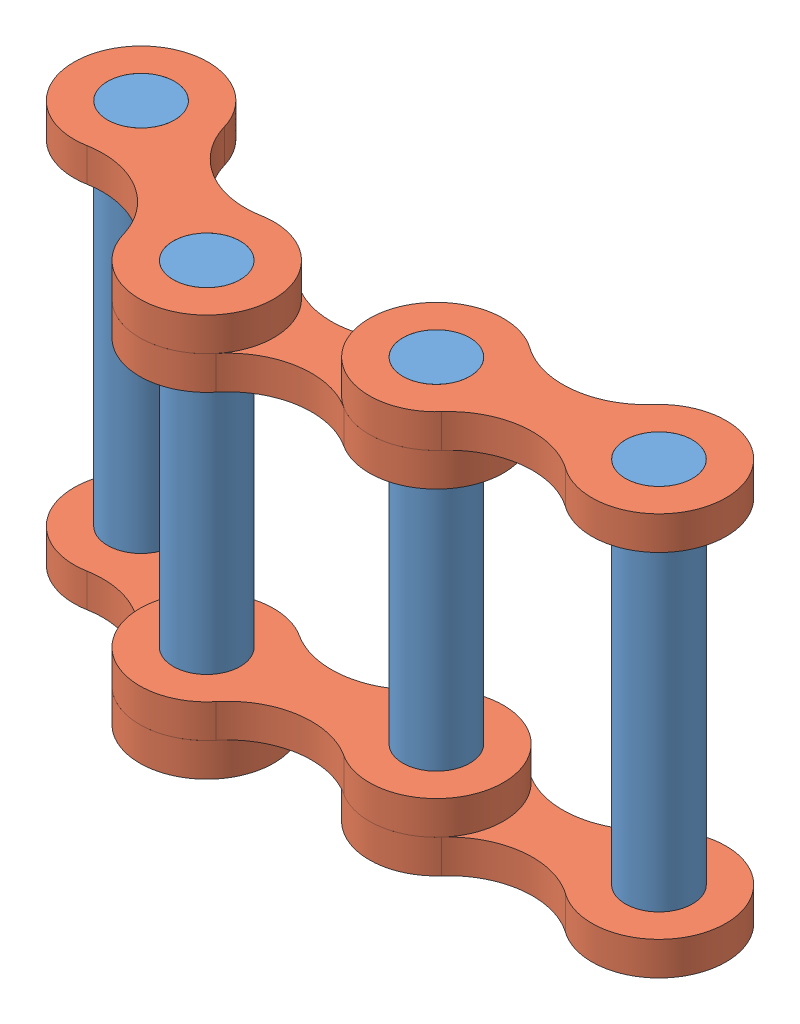
SolidWorks assembly 3linkgearchain, configuration Default. Lengths in mm.
Overall size (10.98 6 4.33).
10 component instances, 2 part files, 23 mates.
Components (placement in the parent):
- bar-1: bar [Default] at (1.6801 0.1043 2.3962) size (1 6 1)
- bar-2: bar [Default] at (-1.2839 0.1043 2.86) x (0.903428 0 0.428741) z (-0.428741 0 0.903428) size (1 6 1)
- bar-3: bar [Default] at (4.6606 0.1043 2.0548) x (-0.977812 0 -0.209483) z (0.209483 0 -0.977812) size (1 6 1)
- link-1: link [Default] at (1.6801 5.6043 2.3962) x (0.993502 0 -0.113816) z (0.113816 0 0.993502) size (5 0.5 2)
- link-2: link [Default] at (-1.2839 5.1043 2.86) x (0.987976 0 -0.154604) z (0.154604 0 0.987976) size (5 0.5 2)
- link-3: link [Default] at (-1.2839 0.6043 2.86) x (0.987976 0 -0.154604) z (0.154604 0 0.987976) size (5 0.5 2)
- link-4: link [Default] at (1.6801 0.1043 2.3962) x (0.993502 0 -0.113816) z (0.113816 0 0.993502) size (5 0.5 2)
- link-6: link [Default] at (-3.8378 5.6043 1.286) x (0.851305 0 0.524672) z (-0.524672 0 0.851305) size (5 0.5 2)
- link-7: link [Default] at (-3.8378 0.1043 1.286) x (0.851305 0 0.524672) z (-0.524672 0 0.851305) size (5 0.5 2)
- bar-5: bar [Default] at (-3.8378 0.1043 1.286) size (1 6 1)
Mates (geometry in assembly coordinates):
- Concentric1: concentric aligned: cylinder of bar-3 through (4.6606 6.1043 2.0548) axis (0 -1 0) radius 0.5; cylinder of link-1 through (4.6606 6.1043 2.0548) axis (0 -1 0) radius 0.5
- Concentric2: concentric aligned: cylinder of bar-1 through (1.6801 6.1043 2.3962) axis (0 -1 0) radius 0.5; cylinder of link-1 through (1.6801 6.1043 2.3962) axis (0 -1 0) radius 0.5
- Concentric3: concentric aligned: cylinder of bar-1 through (1.6801 6.1043 2.3962) axis (0 -1 0) radius 0.5; cylinder of link-2 through (1.6801 5.6043 2.3962) axis (0 -1 0) radius 0.5
- Concentric4: concentric aligned: cylinder of bar-2 through (-1.2839 6.1043 2.86) axis (0 -1 0) radius 0.5; cylinder of link-2 through (-1.2839 5.6043 2.86) axis (0 -1 0) radius 0.5
- Concentric5: concentric aligned: cylinder of bar-2 through (-1.2839 6.1043 2.86) axis (0 -1 0) radius 0.5; cylinder of link-3 through (-1.2839 1.1043 2.86) axis (0 -1 0) radius 0.5
- Concentric6: concentric aligned: cylinder of bar-1 through (1.6801 6.1043 2.3962) axis (0 -1 0) radius 0.5; cylinder of link-4 through (1.6801 0.6043 2.3962) axis (0 -1 0) radius 0.5
- Concentric7: concentric aligned: cylinder of bar-1 through (1.6801 6.1043 2.3962) axis (0 -1 0) radius 0.5; cylinder of link-3 through (1.6801 1.1043 2.3962) axis (0 -1 0) radius 0.5
- Concentric8: concentric aligned: cylinder of bar-3 through (4.6606 6.1043 2.0548) axis (0 -1 0) radius 0.5; cylinder of link-4 through (4.6606 0.6043 2.0548) axis (0 -1 0) radius 0.5
- Coincident1: coincident aligned: plane of bar-3 through (4.6606 6.1043 2.0548) normal (0 1 0); plane of link-1 through (3.8196 6.1043 1.3034) normal (0 1 0)
- Coincident2: coincident aligned: plane of bar-1 through (1.6801 6.1043 2.3962) normal (0 1 0); plane of link-1 through (3.8196 6.1043 1.3034) normal (0 1 0)
- Coincident3: coincident aligned: plane of bar-1 through (1.6801 0.1043 2.3962) normal (0 -1 0); plane of link-4 through (3.8196 0.1043 1.3034) normal (0 -1 0)
- Coincident4: coincident aligned: plane of bar-3 through (4.6606 0.1043 2.0548) normal (0 -1 0); plane of link-4 through (3.8196 0.1043 1.3034) normal (0 -1 0)
- Coincident5: coincident anti-aligned: plane of link-3 through (0.8089 0.6043 1.6801) normal (0 -1 0); plane of link-4 through (3.8196 0.6043 1.3034) normal (0 1 0)
- Coincident6: coincident anti-aligned: plane of link-1 through (3.8196 5.6043 1.3034) normal (0 -1 0); plane of link-2 through (0.8089 5.6043 1.6801) normal (0 1 0)
- Concentric9: concentric aligned: cylinder of bar-2 through (-1.2839 6.1043 2.86) axis (0 -1 0) radius 0.5; cylinder of link-7 through (-1.2839 0.6043 2.86) axis (0 -1 0) radius 0.5
- Concentric10: concentric aligned: cylinder of bar-2 through (-1.2839 6.1043 2.86) axis (0 -1 0) radius 0.5; cylinder of link-6 through (-1.2839 6.1043 2.86) axis (0 -1 0) radius 0.5
- Concentric11: concentric aligned: cylinder of link-6 through (-3.8378 6.1043 1.286) axis (0 -1 0) radius 0.5; cylinder of bar-5 through (-3.8378 6.1043 1.286) axis (0 -1 0) radius 0.5
- Concentric12: concentric aligned: cylinder of link-7 through (-3.8378 0.6043 1.286) axis (0 -1 0) radius 0.5; cylinder of bar-5 through (-3.8378 6.1043 1.286) axis (0 -1 0) radius 0.5
- Coincident7: coincident aligned: plane of link-6 through (-1.4805 6.1043 1.7496) normal (0 1 0); plane of bar-5 through (-3.8378 6.1043 1.286) normal (0 1 0)
- Coincident8: coincident anti-aligned: plane of link-2 through (0.8089 5.6043 1.6801) normal (0 1 0); plane of link-6 through (-1.4805 5.6043 1.7496) normal (0 -1 0)
- Coincident10: coincident anti-aligned: plane of link-3 through (0.8089 0.6043 1.6801) normal (0 -1 0); plane of link-7 through (-1.4805 0.6043 1.7496) normal (0 1 0)
- Coincident11: coincident aligned: plane of link-7 through (-1.4805 0.1043 1.7496) normal (0 -1 0); plane of bar-5 through (-3.8378 0.1043 1.286) normal (0 -1 0)
- Coincident12: coincident aligned: plane of bar-2 through (-1.2839 0.1043 2.86) normal (0 -1 0); plane of link-7 through (-1.4805 0.1043 1.7496) normal (0 -1 0)
